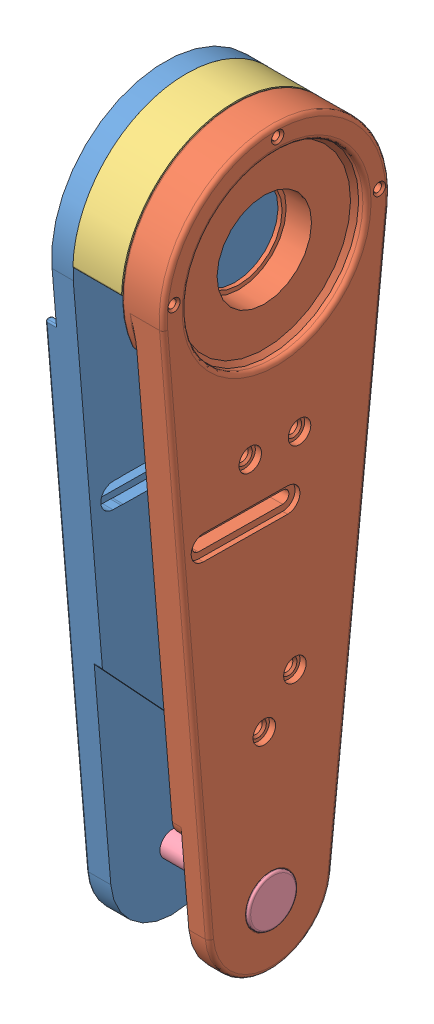
SolidWorks assembly RB_THIGH_LINK, configuration 默认. Lengths in mm.
Overall size (37.36 187.3 93.1).
4 component instances, 4 part files, 8 mates.
Components (placement in the parent):
- 大足-1: 大足 [默认] at (90.65 -1 121.9) x (0 0.010446 0.999945) z (-1 0 0) size (55.2 177.6 19.75)
- 大足2-1: 大足2 [默认] at (105.4 -1 121.9) x (0 -0.010446 -0.999945) z (1 0 0) size (55.62 177.6 10.15)
- 支撑半环-1: 支撑半环 [默认] at (93.55 -1 121.9) x (0 -0.010526 -0.999945) z (0 -0.999945 0.010526) size (55.19 11.85 27.6)
- 字母钉-1: 字母钉 [默认] at (100.85 -135.9926 123.3101) x (0 -0.377975 0.925816) z (0 -0.925816 -0.377975) size (12 30.6 12)
Mates (geometry in assembly coordinates):
- 同心471: concentric anti-aligned: cylinder of 大足-1 through (9.5854 -1 121.9) axis (1 0 0) radius 27.6; cylinder of 支撑半环-1 through (105.4 -1 121.9) axis (-1 0 0) radius 27.6
- 重合187: coincident anti-aligned: plane of 大足-1 through (93.55 -1 121.9) normal (1 0 0); plane of 支撑半环-1 through (93.55 -1 121.9) normal (-1 0 0)
- 同心472: concentric aligned: circle of 大足-1; cylinder of 支撑半环-1 through (93.55 1.2937 146.895) axis (1 0 0) radius 1
- 同心474: concentric aligned: cylinder of 大足-1 through (79.55 -135.9926 123.3101) axis (1 0 0) radius 3.47; cylinder of 大足2-1 through (111.25 -135.9926 123.3101) axis (1 0 0) radius 3.48
- 同心473: concentric aligned: cylinder of 大足2-1 through (115.55 -1 121.9) axis (-1 0 0) radius 27.6; cylinder of 支撑半环-1 through (105.4 -1 121.9) axis (-1 0 0) radius 27.6
- 重合188: coincident anti-aligned: plane of 大足2-1 through (105.4 -1 121.9) normal (-1 0 0); plane of 支撑半环-1 through (105.4 -1 121.9) normal (1 0 0)
- 同心632: concentric aligned: cylinder of 大足2-1 through (111.25 -135.9926 123.3101) axis (1 0 0) radius 3.48; cylinder of 字母钉-1 through (86.55 -135.9926 123.3101) axis (1 0 0) radius 3
- 重合360: coincident anti-aligned: plane of 大足2-1 through (115.15 -135.9926 123.3101) normal (1 0 0); plane of 字母钉-1 through (115.15 -135.9926 123.3101) normal (-1 0 0)
